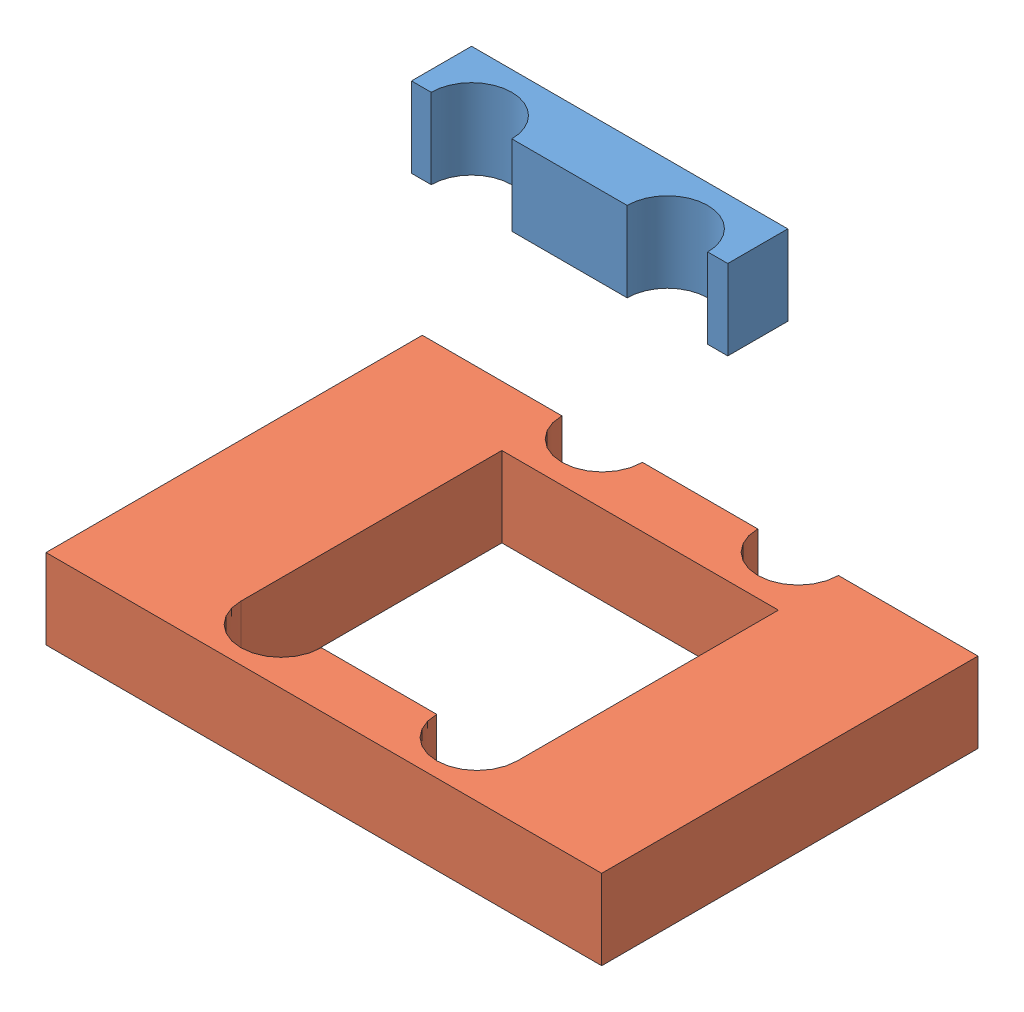
SolidWorks assembly Assem1, configuration Default. Lengths in mm.
Overall size (176.28 118.91 119.38).
2 component instances, 2 part files, 0 mates.
Components (placement in the parent):
- Upper Bolt Installer-1: Upper Bolt Installer [Default] at (18.7999 145.7697 179.1894) size (100.33 25.4 19.05)
- Upper Bolt Installer Middle Part-1: Upper Bolt Installer Middle Part [Default] at (-3.1258 52.258 273.2065) size (176.28 25.4 119.38)
